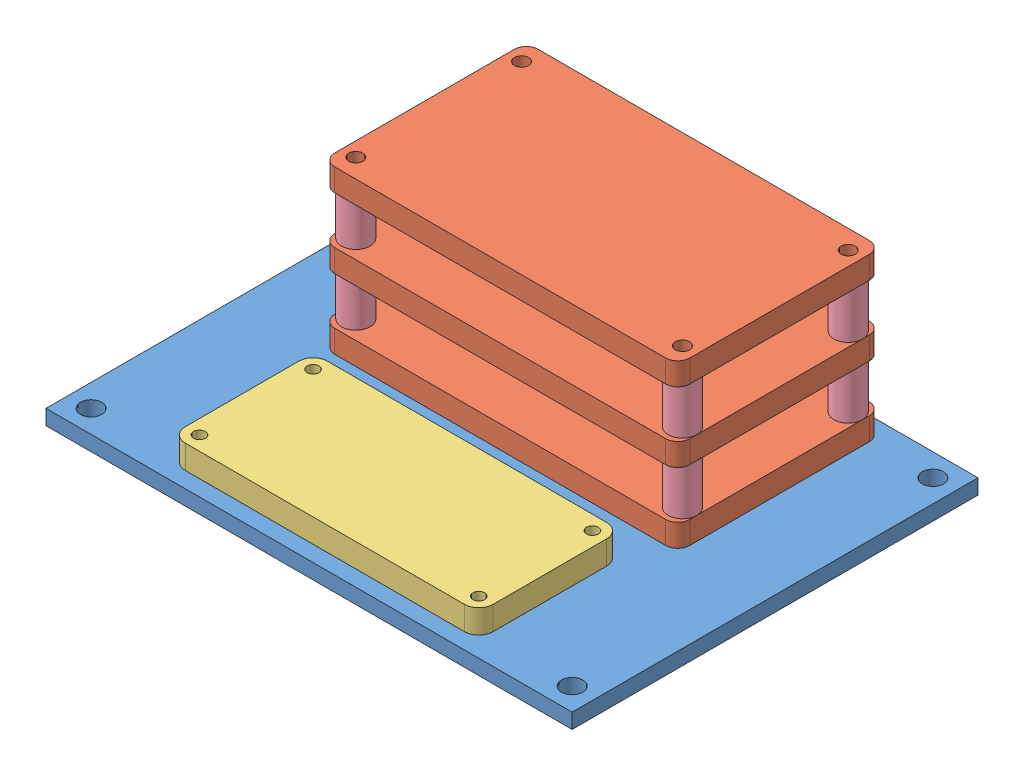
SolidWorks assembly Electrical Mounting, configuration Default. Lengths in mm.
Overall size (111.12 37.46 85.72).
13 component instances, 4 part files, 28 mates.
Components (placement in the parent):
- Electronic Mounting Plate-1: Electronic Mounting Plate [Default] at (19.8066 49.3317 97.3511) size (111.12 3.17 85.72)
- Motor Control Board-1: Motor Control Board [Default] at (19.8066 67.2692 78.3386) size (75 4.76 43)
- Motor Control Board-2: Motor Control Board [Default] at (19.8066 82.0317 78.3386) size (75 4.76 43)
- Motor Control Board-3: Motor Control Board [Default] at (19.8066 52.5067 78.3386) size (75 4.76 43)
- Raspberry Pi-1: Raspberry Pi [Default] at (19.8066 52.5067 121.8636) size (65 5 30)
- 92871A013_SS UNTHRD SPACER-1: 92871A013_SS UNTHRD SPACER [92871A013] at (-14.6934 77.0317 95.8386) x (1 0 0) z (0 -1 0) size (6 6 10)
- 92871A013_SS UNTHRD SPACER-2: 92871A013_SS UNTHRD SPACER [92871A013] at (-14.6934 62.2692 60.8386) x (1 0 0) z (0 -1 0) size (6 6 10)
- 92871A013_SS UNTHRD SPACER-3: 92871A013_SS UNTHRD SPACER [92871A013] at (-14.6934 62.2692 95.8386) x (1 0 0) z (0 -1 0) size (6 6 10)
- 92871A013_SS UNTHRD SPACER-4: 92871A013_SS UNTHRD SPACER [92871A013] at (-14.6934 77.0317 60.8386) x (1 0 0) z (0 -1 0) size (6 6 10)
- 92871A013_SS UNTHRD SPACER-5: 92871A013_SS UNTHRD SPACER [92871A013] at (54.3066 77.0317 60.8386) x (1 0 0) z (0 -1 0) size (6 6 10)
- 92871A013_SS UNTHRD SPACER-6: 92871A013_SS UNTHRD SPACER [92871A013] at (54.3066 77.0317 95.8386) x (1 0 0) z (0 -1 0) size (6 6 10)
- 92871A013_SS UNTHRD SPACER-7: 92871A013_SS UNTHRD SPACER [92871A013] at (54.3066 62.2692 60.8386) x (1 0 0) z (0 -1 0) size (6 6 10)
- 92871A013_SS UNTHRD SPACER-8: 92871A013_SS UNTHRD SPACER [92871A013] at (54.3066 62.2692 95.8386) x (1 0 0) z (0 -1 0) size (6 6 10)
Mates (geometry in assembly coordinates):
- Concentric1: concentric: cylinder of Motor Control Board-1 through (-14.6934 72.0317 95.8386) axis (0 -1 0) radius 1.5; cylinder of Motor Control Board-3 through (-14.6934 57.2692 95.8386) axis (0 -1 0) radius 1.5
- Concentric2: concentric: cylinder of Motor Control Board-1 through (-14.6934 72.0317 95.8386) axis (0 -1 0) radius 1.5; cylinder of Motor Control Board-2 through (-14.6934 86.7942 95.8386) axis (0 -1 0) radius 1.5
- Concentric3: concentric: cylinder of Motor Control Board-1 through (-14.6934 72.0317 60.8386) axis (0 -1 0) radius 1.5; cylinder of Motor Control Board-2 through (-14.6934 86.7942 60.8386) axis (0 -1 0) radius 1.5
- Coincident2: coincident: circle of Motor Control Board-2; cylinder of Motor Control Board-3 through (-14.6934 57.2692 60.8386) axis (0 -1 0) radius 1.5
- Coincident13: coincident: plane of Electronic Mounting Plate-1 through (19.8066 52.5067 97.3511) normal (0 1 0); plane of Motor Control Board-3 through (54.7666 52.5067 59.3786) normal (0 -1 0)
- Coincident14: coincident: plane of Electronic Mounting Plate-1 through (19.8066 52.5067 97.3511) normal (0 1 0); plane of Raspberry Pi-1 through (49.3066 52.5067 109.8636) normal (0 -1 0)
- Concentric12: concentric: cylinder of Motor Control Board-3 through (-14.6934 57.2692 60.8386) axis (0 -1 0) radius 1.5; cylinder of 92871A013_SS UNTHRD SPACER-2 through (-14.6934 57.2692 60.8386) axis (0 1 0) radius 1.6
- Coincident15: coincident: plane of Motor Control Board-3 through (54.7666 57.2692 59.3786) normal (0 1 0); plane of 92871A013_SS UNTHRD SPACER-2 through (-14.6934 57.2692 60.8386) normal (0 -1 0)
- Concentric13: concentric: cylinder of Motor Control Board-3 through (-14.6934 57.2692 95.8386) axis (0 -1 0) radius 1.5; cylinder of 92871A013_SS UNTHRD SPACER-3 through (-14.6934 57.2692 95.8386) axis (0 1 0) radius 1.6
- Coincident16: coincident: plane of Motor Control Board-3 through (54.7666 57.2692 59.3786) normal (0 1 0); plane of 92871A013_SS UNTHRD SPACER-3 through (-14.6934 57.2692 95.8386) normal (0 -1 0)
- Coincident17: coincident: plane of Motor Control Board-1 through (54.7666 67.2692 59.3786) normal (0 -1 0); plane of 92871A013_SS UNTHRD SPACER-3 through (-14.6934 67.2692 95.8386) normal (0 1 0)
- Concentric14: concentric: cylinder of Motor Control Board-3 through (54.3066 57.2692 95.8386) axis (0 -1 0) radius 1.5; cylinder of 92871A013_SS UNTHRD SPACER-8 through (54.3066 57.2692 95.8386) axis (0 1 0) radius 1.6
- Coincident18: coincident: plane of Motor Control Board-3 through (54.7666 57.2692 59.3786) normal (0 1 0); plane of 92871A013_SS UNTHRD SPACER-8 through (54.3066 57.2692 95.8386) normal (0 -1 0)
- Concentric15: concentric: cylinder of Motor Control Board-3 through (54.3066 57.2692 60.8386) axis (0 -1 0) radius 1.5; cylinder of 92871A013_SS UNTHRD SPACER-7 through (54.3066 57.2692 60.8386) axis (0 1 0) radius 1.6
- Coincident19: coincident: plane of Motor Control Board-3 through (54.7666 57.2692 59.3786) normal (0 1 0); plane of 92871A013_SS UNTHRD SPACER-7 through (54.3066 57.2692 60.8386) normal (0 -1 0)
- Concentric16: concentric: cylinder of Motor Control Board-1 through (-14.6934 72.0317 95.8386) axis (0 -1 0) radius 1.5; cylinder of 92871A013_SS UNTHRD SPACER-1 through (-14.6934 72.0317 95.8386) axis (0 1 0) radius 1.6
- Coincident20: coincident: plane of Motor Control Board-1 through (54.7666 72.0317 59.3786) normal (0 1 0); plane of 92871A013_SS UNTHRD SPACER-1 through (-14.6934 72.0317 95.8386) normal (0 -1 0)
- Coincident21: coincident: plane of Motor Control Board-2 through (54.7666 82.0317 59.3786) normal (0 -1 0); plane of 92871A013_SS UNTHRD SPACER-1 through (-14.6934 82.0317 95.8386) normal (0 1 0)
- Concentric17: concentric: cylinder of Motor Control Board-1 through (-14.6934 72.0317 60.8386) axis (0 -1 0) radius 1.5; cylinder of 92871A013_SS UNTHRD SPACER-4 through (-14.6934 72.0317 60.8386) axis (0 1 0) radius 1.6
- Coincident22: coincident: plane of Motor Control Board-1 through (54.7666 72.0317 59.3786) normal (0 1 0); plane of 92871A013_SS UNTHRD SPACER-4 through (-14.6934 72.0317 60.8386) normal (0 -1 0)
- Concentric18: concentric: cylinder of Motor Control Board-1 through (54.3066 72.0317 60.8386) axis (0 -1 0) radius 1.5; cylinder of 92871A013_SS UNTHRD SPACER-5 through (54.3066 72.0317 60.8386) axis (0 1 0) radius 1.6
- Coincident23: coincident: plane of Motor Control Board-1 through (54.7666 72.0317 59.3786) normal (0 1 0); plane of 92871A013_SS UNTHRD SPACER-5 through (54.3066 72.0317 60.8386) normal (0 -1 0)
- Concentric19: concentric: cylinder of Motor Control Board-1 through (54.3066 72.0317 95.8386) axis (0 -1 0) radius 1.5; cylinder of 92871A013_SS UNTHRD SPACER-6 through (54.3066 72.0317 95.8386) axis (0 1 0) radius 1.6
- Coincident24: coincident: plane of Motor Control Board-1 through (54.7666 72.0317 59.3786) normal (0 1 0); plane of 92871A013_SS UNTHRD SPACER-6 through (54.3066 72.0317 95.8386) normal (0 -1 0)
- Concentric20: concentric: cylinder of Electronic Mounting Plate-1 through (49.3066 52.5067 109.8636) axis (0 1 0) radius 2.25; cylinder of Raspberry Pi-1 through (49.3066 57.5067 109.8636) axis (0 -1 0) radius 1.25
- Concentric21: concentric: cylinder of Electronic Mounting Plate-1 through (-9.6934 52.5067 133.8636) axis (0 1 0) radius 2.25; cylinder of Raspberry Pi-1 through (-9.6934 57.5067 133.8636) axis (0 -1 0) radius 1.25
- Concentric22: concentric: cylinder of Electronic Mounting Plate-1 through (-14.6934 52.5067 95.8386) axis (0 1 0) radius 2.25; cylinder of Motor Control Board-3 through (-14.6934 57.2692 95.8386) axis (0 -1 0) radius 1.5
- Concentric23: concentric: cylinder of Electronic Mounting Plate-1 through (54.3066 52.5067 60.8386) axis (0 1 0) radius 2.25; cylinder of Motor Control Board-3 through (54.3066 57.2692 60.8386) axis (0 -1 0) radius 1.5
